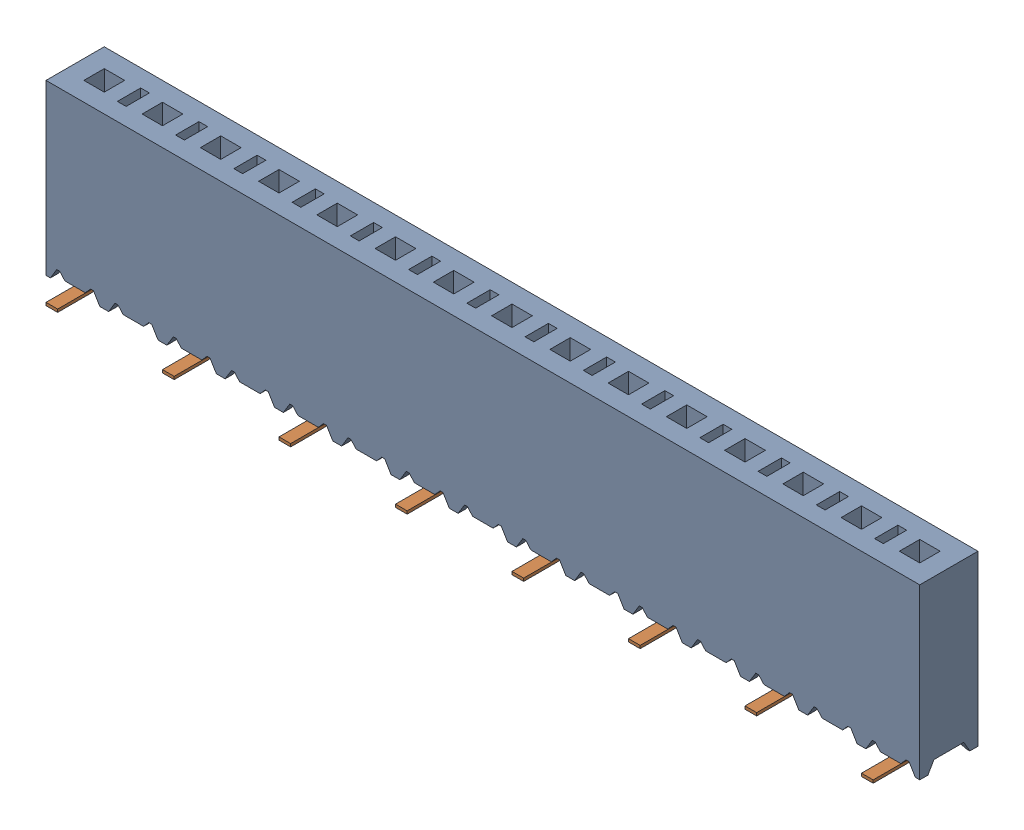
SolidWorks assembly SSM_115_L_SV, configuration Default. Lengths in mm.
Overall size (38.1 7.49 4.57).
2 component instances, 2 part files, 0 mates.
Components (placement in the parent):
- _SSM_115_L_SV_body_2-1: _SSM_115_L_SV_body_2 [Default] at origin size (38.1 7.37 2.54)
- _C_95_0215_4-1: _C_95_0215_4 [Default] at (0 -0.127 0) size (36.07 1.91 4.57)
